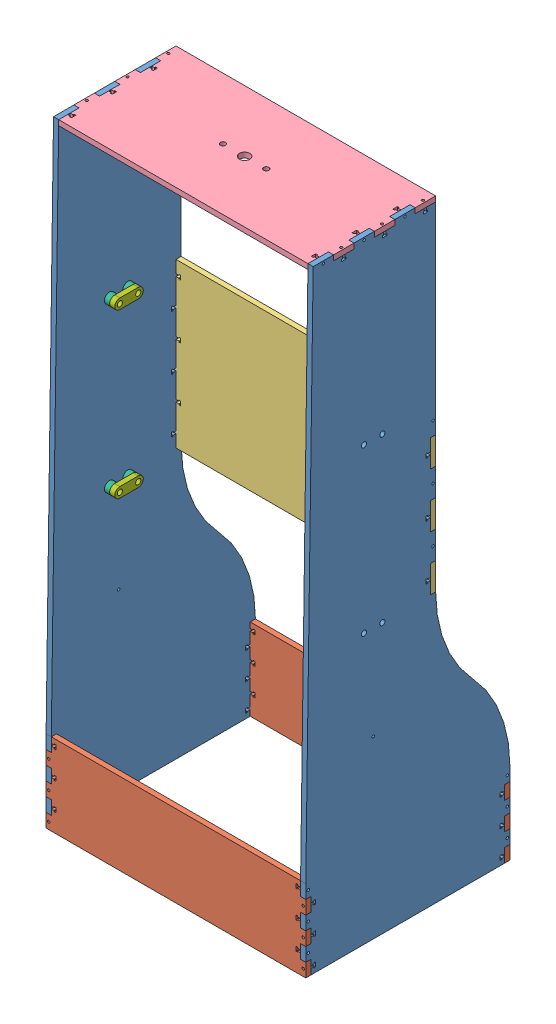
SolidWorks assembly Final Soap Film Tunnel, configuration Default. Lengths in mm.
Overall size (318 750 250).
11 component instances, 7 part files, 28 mates.
Components (placement in the parent):
- Part1^Final Soap Film Tunnel-1: Part1^Final Soap Film Tunnel [Default] x (0 0 -1) z (1 0 0) size (250 750 6.35) (virtual)
- Part2^Final Soap Film Tunnel-1: Part2^Final Soap Film Tunnel [Default] at origin size (318 100 6.35) (virtual)
- Part3^Final Soap Film Tunnel-1: Part3^Final Soap Film Tunnel [Default] at (0 0 -159.0763) x (-1 0 0) z (0 0 -1) size (318 200 6.35) (virtual)
- Part4^Final Soap Film Tunnel-1: Part4^Final Soap Film Tunnel [Default] at (0 750 0) x (0 0 -1) z (0 1 0) size (150 318 6.35) (virtual)
- Part5^Final Soap Film Tunnel-1: Part5^Final Soap Film Tunnel [Default] at (0 743.65 0) x (0 0 1) z (0 -1 0) size (19.7 72.7 6.35) (virtual)
- Part1^Final Soap Film Tunnel-2: Part1^Final Soap Film Tunnel [Default] at (311.65 0 0) x (0 0 -1) z (1 0 0) size (250 750 6.35) (virtual)
- Part2^Final Soap Film Tunnel-2: Part2^Final Soap Film Tunnel [Default] at (0 0 -243.65) size (318 100 6.35) (virtual)
- Part6^Final Soap Film Tunnel-1: Part6^Final Soap Film Tunnel [Default] at (6.35 0 0) x (0 0 -1) z (1 0 0) size (34.85 212.35 6.35) (virtual)
- Part7^Final Soap Film Tunnel-1: Part7^Final Soap Film Tunnel [Default] at (12.7 0 0) x (0 0 -1) z (1 0 0) size (34.85 212.35 6.35) (virtual)
- Part6^Final Soap Film Tunnel-2: Part6^Final Soap Film Tunnel [Default] at (305.3 0 0) x (0 0 -1) z (1 0 0) size (34.85 212.35 6.35) (virtual)
- Part7^Final Soap Film Tunnel-2: Part7^Final Soap Film Tunnel [Default] at (298.95 860 -165.0806) x (0 0 1) z (1 0 0) size (34.85 212.35 6.35) (virtual)
Mates (geometry in assembly coordinates):
- InPlace1: in place: plane of Part1^Final Soap Film Tunnel-1 through (0 0 0) normal (1 0 0); moOrthogonalPlaneRef_w of Part1^Final Soap Film Tunnel-1 through (0 0 0) normal (0 1 0); plane of Part1^Final Soap Film Tunnel-1 through (0 0 0) normal (0 0 -1); unknown of Part1^Final Soap Film Tunnel-1
- Coincident1: coincident: plane of Part1^Final Soap Film Tunnel-1; plane of assembly
- Coincident2: coincident: plane of Part1^Final Soap Film Tunnel-1 through (0 0 0) normal (0 1 0); moOrthogonalPlaneRef_w of assembly
- Coincident3: coincident: plane of Part1^Final Soap Film Tunnel-1 through (0 0 0) normal (0 0 -1); moOrthogonalPlaneRef_w of assembly
- InPlace2: in place: plane of Part2^Final Soap Film Tunnel-1 through (0 0 0) normal (0 0 1); plane of Part2^Final Soap Film Tunnel-1 through (0 0 0) normal (0 1 0); plane of Part2^Final Soap Film Tunnel-1 through (0 0 0) normal (1 0 0); unknown of Part2^Final Soap Film Tunnel-1
- Coincident4: coincident: plane of Part2^Final Soap Film Tunnel-1; plane of assembly
- Coincident5: coincident: plane of Part2^Final Soap Film Tunnel-1 through (0 0 0) normal (0 1 0); moOrthogonalPlaneRef_w of assembly
- Coincident6: coincident: plane of Part2^Final Soap Film Tunnel-1 through (0 0 0) normal (1 0 0); moOrthogonalPlaneRef_w of assembly
- InPlace3: in place: plane of Part1^Final Soap Film Tunnel-1 through (6.35 750 -159.0763) normal (0 0 -1); plane of Part3^Final Soap Film Tunnel-1 through (0 0 -159.0763) normal (0 0 -1); plane of Part1^Final Soap Film Tunnel-1 through (6.35 750 -159.0763) normal (0 0 -1); plane of Part3^Final Soap Film Tunnel-1 through (0 0 -159.0763) normal (0 1 0); plane of Part1^Final Soap Film Tunnel-1 through (6.35 750 -159.0763) normal (0 0 -1); plane of Part3^Final Soap Film Tunnel-1 through (0 0 -159.0763) normal (-1 0 0); plane of Part1^Final Soap Film Tunnel-1 through (6.35 750 -159.0763) normal (0 0 -1); unknown of Part3^Final Soap Film Tunnel-1
- Coincident7: coincident: plane of Part1^Final Soap Film Tunnel-1; plane of Part3^Final Soap Film Tunnel-1
- Coincident8: coincident: moOrthogonalPlaneRef_w of Part1^Final Soap Film Tunnel-1 through (0 0 -159.0763) normal (0 1 0); plane of Part3^Final Soap Film Tunnel-1 through (0 0 -159.0763) normal (0 1 0)
- Coincident9: coincident: moOrthogonalPlaneRef_w of Part1^Final Soap Film Tunnel-1 through (0 0 -159.0763) normal (1 0 0); plane of Part3^Final Soap Film Tunnel-1 through (0 0 -159.0763) normal (-1 0 0)
- InPlace4: in place: plane of Part1^Final Soap Film Tunnel-1 through (6.35 750 -9.0763) normal (0 1 0); plane of ? through (0 750 0) normal (0 1 0); plane of Part1^Final Soap Film Tunnel-1 through (6.35 750 -9.0763) normal (0 1 0); plane of ? through (0 750 0) normal (0 0 -1); plane of Part1^Final Soap Film Tunnel-1 through (6.35 750 -9.0763) normal (0 1 0); plane of ? through (0 750 0) normal (1 0 0); plane of Part1^Final Soap Film Tunnel-1 through (6.35 750 -9.0763) normal (0 1 0); unknown of Part4^Final Soap Film Tunnel-1
- Coincident10: coincident: plane of Part1^Final Soap Film Tunnel-1; plane of Part4^Final Soap Film Tunnel-1
- Coincident11: coincident: moOrthogonalPlaneRef_w of Part1^Final Soap Film Tunnel-1 through (0 750 0) normal (-1 0 0); plane of Part4^Final Soap Film Tunnel-1 through (0 750 0) normal (-1 0 0)
- Coincident12: coincident: moOrthogonalPlaneRef_w of Part1^Final Soap Film Tunnel-1 through (0 750 0) normal (0 0 1); plane of Part4^Final Soap Film Tunnel-1 through (0 750 0) normal (0 0 -1)
- InPlace5: in place: plane of Part4^Final Soap Film Tunnel-1 through (0 743.65 0) normal (0 -1 0); plane of ? through (0 743.65 0) normal (0 -1 0); plane of Part4^Final Soap Film Tunnel-1 through (0 743.65 0) normal (0 -1 0); plane of ? through (0 743.65 0) normal (0 0 -1); plane of Part4^Final Soap Film Tunnel-1 through (0 743.65 0) normal (0 -1 0); plane of ? through (0 743.65 0) normal (-1 0 0); plane of Part4^Final Soap Film Tunnel-1 through (0 743.65 0) normal (0 -1 0); unknown of Part5^Final Soap Film Tunnel-1
- Coincident13: coincident: plane of Part4^Final Soap Film Tunnel-1; plane of Part5^Final Soap Film Tunnel-1
- Coincident14: coincident: moOrthogonalPlaneRef_w of Part4^Final Soap Film Tunnel-1 through (0 743.65 0) normal (-1 0 0); plane of Part5^Final Soap Film Tunnel-1 through (0 743.65 0) normal (-1 0 0)
- Coincident15: coincident: moOrthogonalPlaneRef_w of Part4^Final Soap Film Tunnel-1 through (0 743.65 0) normal (0 0 -1); plane of Part5^Final Soap Film Tunnel-1 through (0 743.65 0) normal (0 0 1)
- InPlace6: in place: plane of Part1^Final Soap Film Tunnel-1 through (6.35 330 -327.2589) normal (1 0 0); plane of Part6^Final Soap Film Tunnel-1 through (6.35 0 0) normal (1 0 0); plane of Part1^Final Soap Film Tunnel-1 through (6.35 330 -327.2589) normal (1 0 0); plane of Part6^Final Soap Film Tunnel-1 through (6.35 0 0) normal (0 1 0); plane of Part1^Final Soap Film Tunnel-1 through (6.35 330 -327.2589) normal (1 0 0); plane of Part6^Final Soap Film Tunnel-1 through (6.35 0 0) normal (0 0 -1); plane of Part1^Final Soap Film Tunnel-1 through (6.35 330 -327.2589) normal (1 0 0); unknown of Part6^Final Soap Film Tunnel-1
- Coincident1: coincident: plane of Part1^Final Soap Film Tunnel-1; plane of Part6^Final Soap Film Tunnel-1
- Coincident2: coincident: moOrthogonalPlaneRef_w of Part1^Final Soap Film Tunnel-1 through (6.35 0 0) normal (0 1 0); plane of Part6^Final Soap Film Tunnel-1 through (6.35 0 0) normal (0 1 0)
- Coincident3: coincident: moOrthogonalPlaneRef_w of Part1^Final Soap Film Tunnel-1 through (6.35 0 0) normal (0 0 1); plane of Part6^Final Soap Film Tunnel-1 through (6.35 0 0) normal (0 0 -1)
- InPlace7: in place: plane of Part6^Final Soap Film Tunnel-1 through (22.7 530 -93.7903) normal (1 0 0); plane of ? through (22.7 0 0) normal (1 0 0); plane of Part6^Final Soap Film Tunnel-1 through (22.7 530 -93.7903) normal (1 0 0); plane of ? through (22.7 0 0) normal (0 1 0); plane of Part6^Final Soap Film Tunnel-1 through (22.7 530 -93.7903) normal (1 0 0); plane of ? through (22.7 0 0) normal (0 0 -1); plane of Part6^Final Soap Film Tunnel-1 through (12.7 530 -93.7903) normal (1 0 0); unknown of Part7^Final Soap Film Tunnel-1
- Coincident4: coincident: plane of Part6^Final Soap Film Tunnel-1; plane of Part7^Final Soap Film Tunnel-1
- Coincident5: coincident: moOrthogonalPlaneRef_w of Part6^Final Soap Film Tunnel-1 through (12.7 0 0) normal (0 1 0); plane of Part7^Final Soap Film Tunnel-1 through (12.7 0 0) normal (0 1 0)
- Coincident6: coincident: moOrthogonalPlaneRef_w of Part6^Final Soap Film Tunnel-1 through (12.7 0 0) normal (0 0 1); plane of Part7^Final Soap Film Tunnel-1 through (12.7 0 0) normal (0 0 -1)
